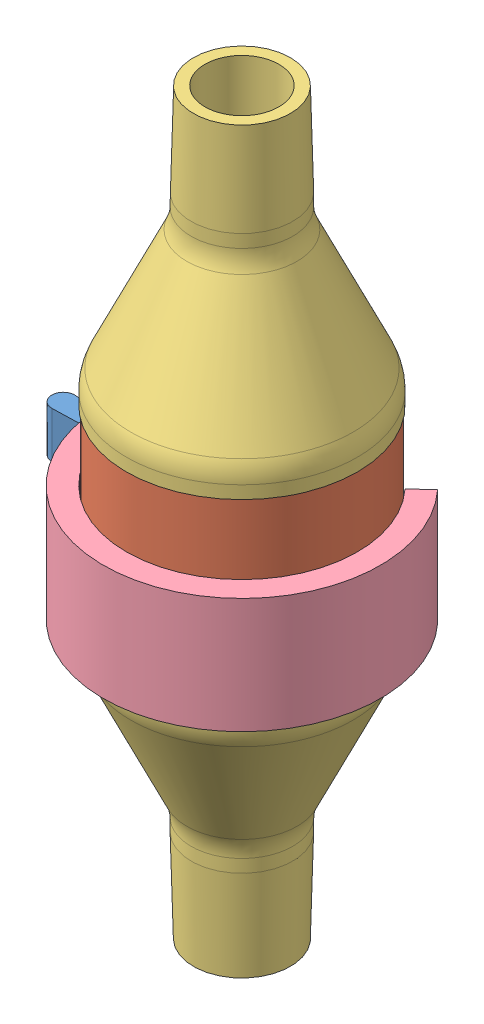
SolidWorks assembly Montagem_válvula, configuration Valor predeterminado. Lengths in mm.
Overall size (77.23 160.31 68.1).
5 component instances, 4 part files, 7 mates.
Components (placement in the parent):
- Catraca-1: Catraca [Valor predeterminado] at (175.8505 156.8441 107.4307) x (0.028247 0 0.999601) z (0 -1 0) size (35.53 67.25 10)
- Peça 3-1: Peça 3 [Valor predeterminado] at (175.8505 176.8441 107.4307) x (0 0 1) z (1 0 0) size (49.5 35 49.5)
- Peça 1 - Funil-1: Peça 1 - Funil [Valor predeterminado] at (175.8505 131.8441 107.4307) x (0.871355 0 0.490653) z (0 1 0) size (50 50 60.16)
- Peça 1 - Funil-2: Peça 1 - Funil [Valor predeterminado] at (175.8505 181.8441 107.4307) x (0.897976 0 0.440044) z (0 -1 0) size (50 50 60.16)
- Peça 2-2: Peça 2 [Valor predeterminado] at (175.8505 136.8441 107.4307) size (59.99 25 55)
Mates (geometry in assembly coordinates):
- Coincident24: coincident: circle of assembly; circle of assembly; circle of Peça 3-1; circle of Peça 1 - Funil-2
- Coincident25: coincident: circle of assembly; circle of assembly; circle of Catraca-1; circle of Peça 2-2
- Coincident26: coincident: circle of assembly; circle of assembly; circle of Peça 1 - Funil-1; circle of Peça 2-2
- Concentric7: concentric: cylinder of assembly; circle of assembly; cylinder of Peça 3-1 through (175.8505 141.8441 107.4307) axis (0 1 0) radius 2.5; circle of Peça 2-2
- Concentric9: concentric: cylinder of assembly; circle of assembly; cylinder of Peça 3-1 through (175.8505 141.8441 116.4307) axis (0 1 0) radius 2.5; circle of Peça 2-2
- Coincident31: coincident: plane of assembly; plane of assembly; plane of Peça 3-1 through (175.8505 146.8441 107.4307) normal (0 -1 0); plane of Peça 2-2 through (175.8505 146.8441 107.4307) normal (0 1 0)
- LimitAngle1: limit planar angle = 2.297726 rad: plane of assembly; plane of assembly; plane of Catraca-1 through (175.8505 146.8441 107.4307) normal (0.095956 0 -0.995386); plane of Peça 2-2 through (175.8505 58.4944 107.4307) normal (-0.68 0 -0.733212)
